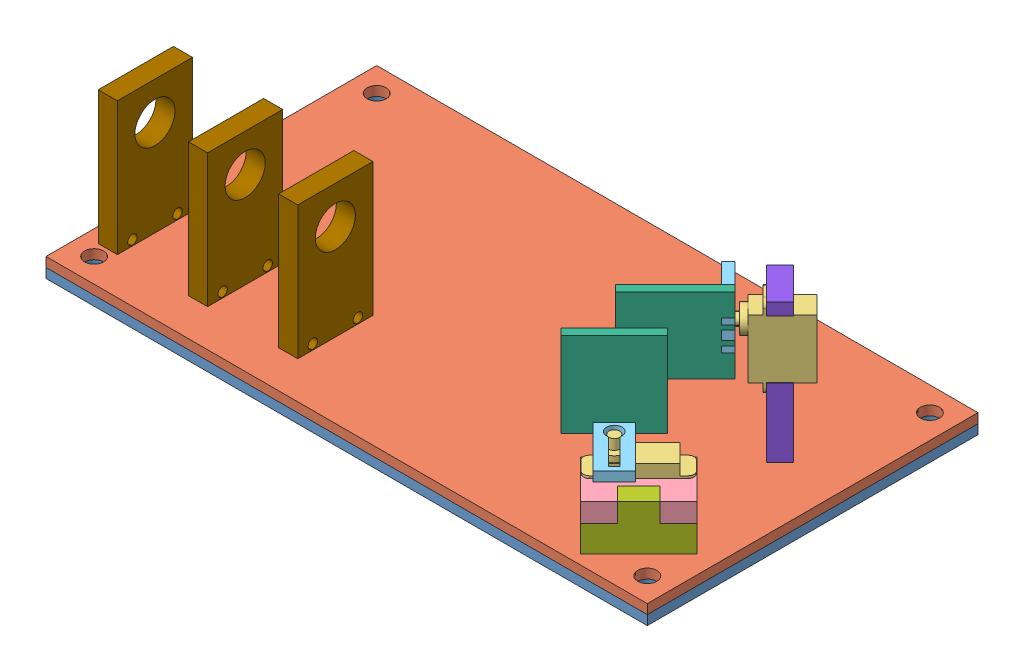
SolidWorks assembly Top Level Assembly, configuration Default. Lengths in mm.
Overall size (200 57.1 123.79).
16 component instances, 9 part files, 10 mates.
Components (placement in the parent):
- Base Plate_ Bottom-1: Base Plate_ Bottom [Default] at origin size (200 3.17 110)
- Base Plate_ Top-1: Base Plate_ Top [Default] at (0 3.175 0) size (200 3.17 110)
- X-Servo and Mounts-1: X-Servo and Mounts [Default] at (136.2321 -16.4203 -35.1414) x (0.707107 0 -0.707107) z (0.707107 0 0.707107) size (31.9 53.92 23)
  - Servo PowerHD DSP33-1: Servo PowerHD DSP33 [Default] at (8.4865 26.0453 40.4597) size (27.17 21.7 8.4)
  - Servo Mounts-1: Servo Mounts [Default] at (8.4865 31.5953 40.4597) size (27.4 6.35 18.05)
  - Servo Cap Mount-1: Servo Cap Mount [Default] at (7.4865 45.3453 52.4122) size (10 3.17 23)
  - Mirror Mount-1: Mirror Mount [Default] at (-0.0135 73.5203 32.5872) x (1 0 0) z (0 1 0) size (25 3.17 28.17)
  - x-servo Riser-1: x-servo Riser [Default] at (4.4865 19.5953 49.8097) size (27.4 18.35 6.35)
- Y-Servo and Mounts-1: Y-Servo and Mounts [Default] at (231.7255 58.9192 -70.462) x (0 -1 0) z (-0.707107 0 -0.707107) size (53.9 47.47 23)
  - Servo PowerHD DSP33-1: Servo PowerHD DSP33 [Default] at (10.3442 32.3124 38.838) size (27.17 21.7 8.4)
  - Servo Cap Mount-1: Servo Cap Mount [Default] at (9.3442 51.6124 50.7904) size (10 3.17 23)
  - Mirror Mount-1: Mirror Mount [Default] at (1.8442 79.7874 30.9654) x (1 0 0) z (0 1 0) size (25 3.17 28.17)
  - Y-Servo Mount-1: Y-Servo Mount [Default] at (10.3442 37.8624 38.838) size (49.4 6.35 15.05)
- Laser Holder-1: Laser Holder [Default] at (5 50.675 -37.3892) x (0 0 1) z (0 1 0) size (25 6.35 47.5)
- Laser Holder-15: Laser Holder [Default] at (35 50.675 -37.3892) x (0 0 1) z (0 1 0) size (25 6.35 47.5)
- Laser Holder-16: Laser Holder [Default] at (65 50.675 -37.3892) x (0 0 1) z (0 1 0) size (25 6.35 47.5)
Mates (geometry in assembly coordinates):
- Coincident1: coincident: point of Base Plate_ Bottom-1; point of Base Plate_ Top-1
- Coincident2: coincident: point of Base Plate_ Bottom-1; point of Base Plate_ Top-1
- Coincident3: coincident: point of Base Plate_ Bottom-1; point of Base Plate_ Top-1
- Coincident19: coincident: point of Base Plate_ Top-1; point of X-Servo and Mounts-1/x-servo Riser-1
- Coincident20: coincident: point of Base Plate_ Top-1; point of X-Servo and Mounts-1/x-servo Riser-1
- Coincident21: coincident: point of Base Plate_ Top-1; point of Y-Servo and Mounts-1/Y-Servo Mount-1
- Coincident22: coincident: point of Base Plate_ Top-1; point of Y-Servo and Mounts-1/Y-Servo Mount-1
- Coincident23: coincident: point of Base Plate_ Top-1; point of Laser Holder-1
- Coincident24: coincident: point of Base Plate_ Top-1; point of Laser Holder-1
- Coincident25: coincident: plane of Base Plate_ Bottom-1 through (0 3.175 0) normal (0 1 0); line of Laser Holder-1 through (11.35 3.175 -12.3892) axis (0 0 -1)
